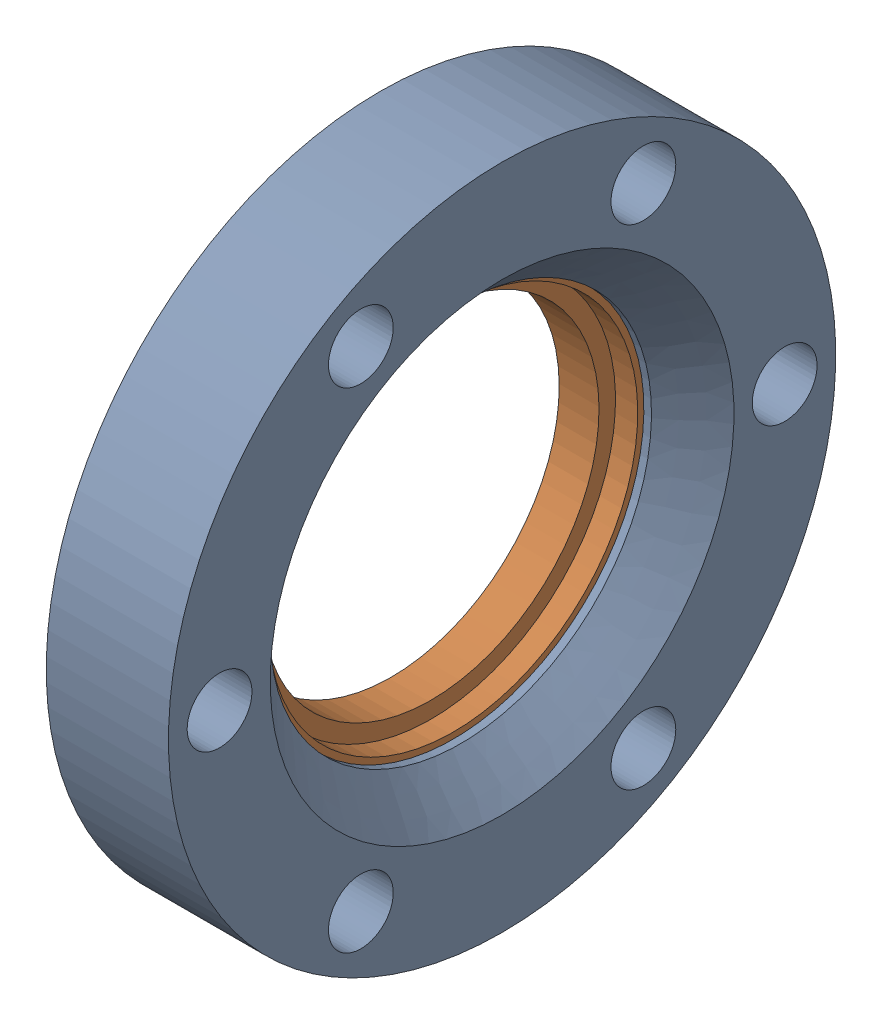
SolidWorks assembly 100014 (2.75 X 1.5 R), configuration Default. Lengths in mm.
Overall size (12.7 69.34 69.34).
2 component instances, 2 part files, 0 mates.
Components (placement in the parent):
- 100014 (2.75 X 1.5 REC)_1-1: 100014 (2.75 X 1.5 REC)_1 [Default] at origin size (12.7 69.34 69.34)
- 100014 (2.75 X 1.5 INS)-1: 100014 (2.75 X 1.5 INS) [Default] at (1.17 0 0) x (1 0 0) z (0 0.994423 -0.105464) size (6.96 48.1 48.1)
